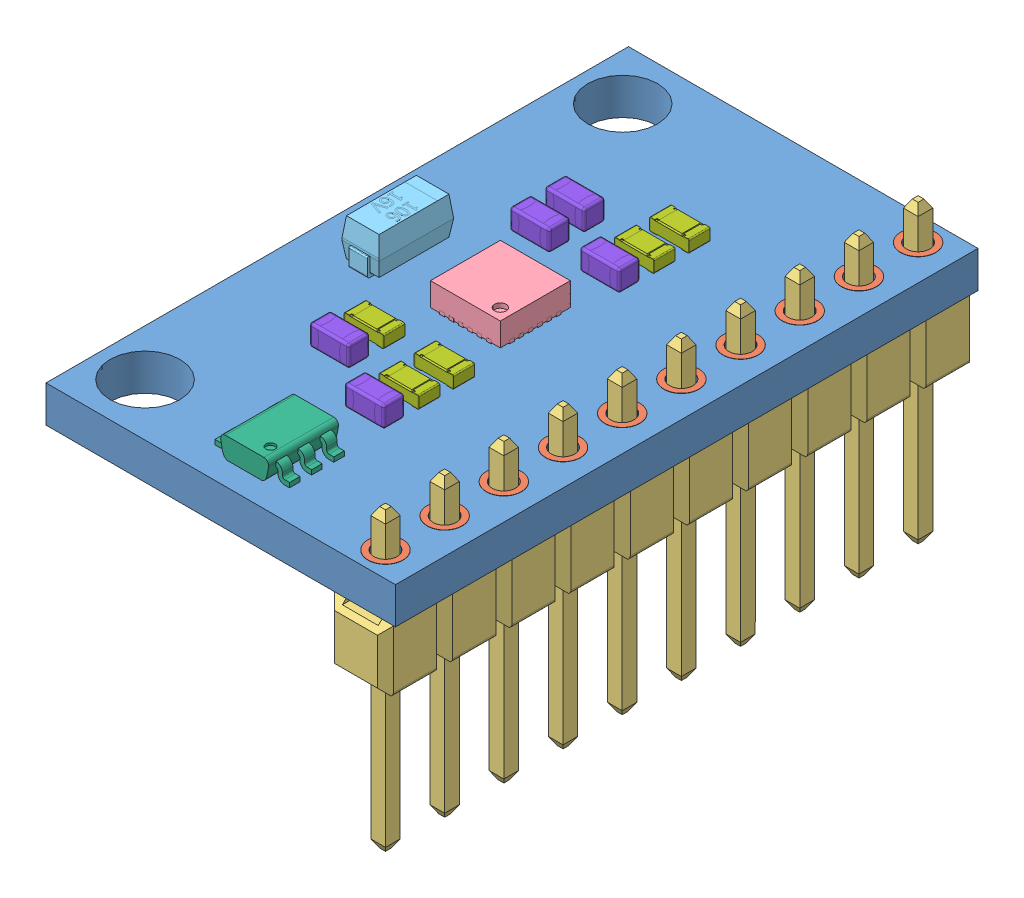
SolidWorks assembly MPU-9250, configuration Default. Lengths in mm.
Overall size (15 12.78 25.41).
36 component instances, 8 part files, 0 mates.
Components (placement in the parent):
- MPU-9250.stp-1: MPU-9250.stp [Default] at origin size (15 12.78 25.41)
  - board.stp-1: board.stp [Default] at (-7.5 -1.57 12.5) size (15 1.57 25)
  - hole_plating.stp-1: hole_plating.stp [Default] at (-1.5 0 23.93) size (1.5 0.01 1.5)
  - hole_plating.stp-2: hole_plating.stp [Default] at (-1.5 0 21.39) size (1.5 0.01 1.5)
  - hole_plating.stp-3: hole_plating.stp [Default] at (-1.5 0 8.69) size (1.5 0.01 1.5)
  - hole_plating.stp-4: hole_plating.stp [Default] at (-1.5 -1.58 13.77) size (1.5 0.01 1.5)
  - hole_plating.stp-5: hole_plating.stp [Default] at (-1.5 0 16.31) size (1.5 0.01 1.5)
  - hole_plating.stp-6: hole_plating.stp [Default] at (-1.5 0 18.85) size (1.5 0.01 1.5)
  - hole_plating.stp-7: hole_plating.stp [Default] at (-1.5 0 13.77) size (1.5 0.01 1.5)
  - hole_plating.stp-8: hole_plating.stp [Default] at (-1.5 -1.58 11.23) size (1.5 0.01 1.5)
  - hole_plating.stp-9: hole_plating.stp [Default] at (-1.5 -1.58 18.85) size (1.5 0.01 1.5)
  - hole_plating.stp-10: hole_plating.stp [Default] at (-1.5 -1.58 6.15) size (1.5 0.01 1.5)
  - hole_plating.stp-11: hole_plating.stp [Default] at (-1.5 0 1.07) size (1.5 0.01 1.5)
  - hole_plating.stp-12: hole_plating.stp [Default] at (-1.5 -1.58 3.61) size (1.5 0.01 1.5)
  - hole_plating.stp-13: hole_plating.stp [Default] at (-1.5 -1.58 1.07) size (1.5 0.01 1.5)
  - hole_plating.stp-14: hole_plating.stp [Default] at (-1.5 -1.58 8.69) size (1.5 0.01 1.5)
  - hole_plating.stp-15: hole_plating.stp [Default] at (-1.5 -1.58 16.31) size (1.5 0.01 1.5)
  - hole_plating.stp-16: hole_plating.stp [Default] at (-1.5 0 11.23) size (1.5 0.01 1.5)
  - hole_plating.stp-17: hole_plating.stp [Default] at (-1.5 0 3.61) size (1.5 0.01 1.5)
  - hole_plating.stp-18: hole_plating.stp [Default] at (-1.5 -1.58 21.39) size (1.5 0.01 1.5)
  - hole_plating.stp-19: hole_plating.stp [Default] at (-1.5 0 6.15) size (1.5 0.01 1.5)
  - hole_plating.stp-20: hole_plating.stp [Default] at (-1.5 -1.58 23.93) size (1.5 0.01 1.5)
  - Pin Header 1x10 TH Pitch 2.54mm.stp-1: Pin Header 1x10 TH Pitch 2.54mm.stp [Default] at (-1.5 -1.5786 23.93) x (0 0 -1) z (0 -1 0) size (25.41 2.55 12.7)
  - MPU-9250_1.stp-1: MPU-9250_1.stp [Default] at (-8 0.05 12.5) x (-1 0 0) z (0 1 0) size (3 3 1.05)
  - tantalum 10uF.stp-1: tantalum 10uF.stp [Default] at (-13.167 0.1 10.9372) x (0 0 1) z (0 1 0) size (3.41 1.61 1.71)
  - SOT23_5.stp-1: SOT23_5.stp [Default] at (-7.475 -0.0136 21) x (0 0 1) z (0 1 0) size (3.01 3.21 0.92)
  - RESC-0603.stp-1: RESC-0603.stp [Default] at (-6.85 0 7.45) x (1 0 0) z (0 1 0) size (1.7 0.9 0.55)
  - RESC-0603.stp-2: RESC-0603.stp [Default] at (-9.85 0 16.05) x (1 0 0) z (0 1 0) size (1.7 0.9 0.55)
  - RESC-0603.stp-3: RESC-0603.stp [Default] at (-6.85 0 17.55) x (1 0 0) z (0 1 0) size (1.7 0.9 0.55)
  - RESC-0603.stp-4: RESC-0603.stp [Default] at (-6.85 0 16.05) x (1 0 0) z (0 1 0) size (1.7 0.9 0.55)
  - RESC-0603.stp-5: RESC-0603.stp [Default] at (-6.85 0 5.95) x (1 0 0) z (0 1 0) size (1.7 0.9 0.55)
  - CAPC-0603-T0.9-BN.stp-1: CAPC-0603-T0.9-BN.stp [Default] at (-9.85 0 8.95) x (1 0 0) z (0 1 0) size (1.7 0.9 0.9)
  - CAPC-0603-T0.9-BN.stp-2: CAPC-0603-T0.9-BN.stp [Default] at (-6.85 0 8.95) x (1 0 0) z (0 1 0) size (1.7 0.9 0.9)
  - CAPC-0603-T0.9-BN.stp-3: CAPC-0603-T0.9-BN.stp [Default] at (-6.85 0 19.05) x (1 0 0) z (0 1 0) size (1.7 0.9 0.9)
  - CAPC-0603-T0.9-BN.stp-4: CAPC-0603-T0.9-BN.stp [Default] at (-9.85 0 7.45) x (1 0 0) z (0 1 0) size (1.7 0.9 0.9)
  - CAPC-0603-T0.9-BN.stp-5: CAPC-0603-T0.9-BN.stp [Default] at (-9.85 0 17.55) x (1 0 0) z (0 1 0) size (1.7 0.9 0.9)
